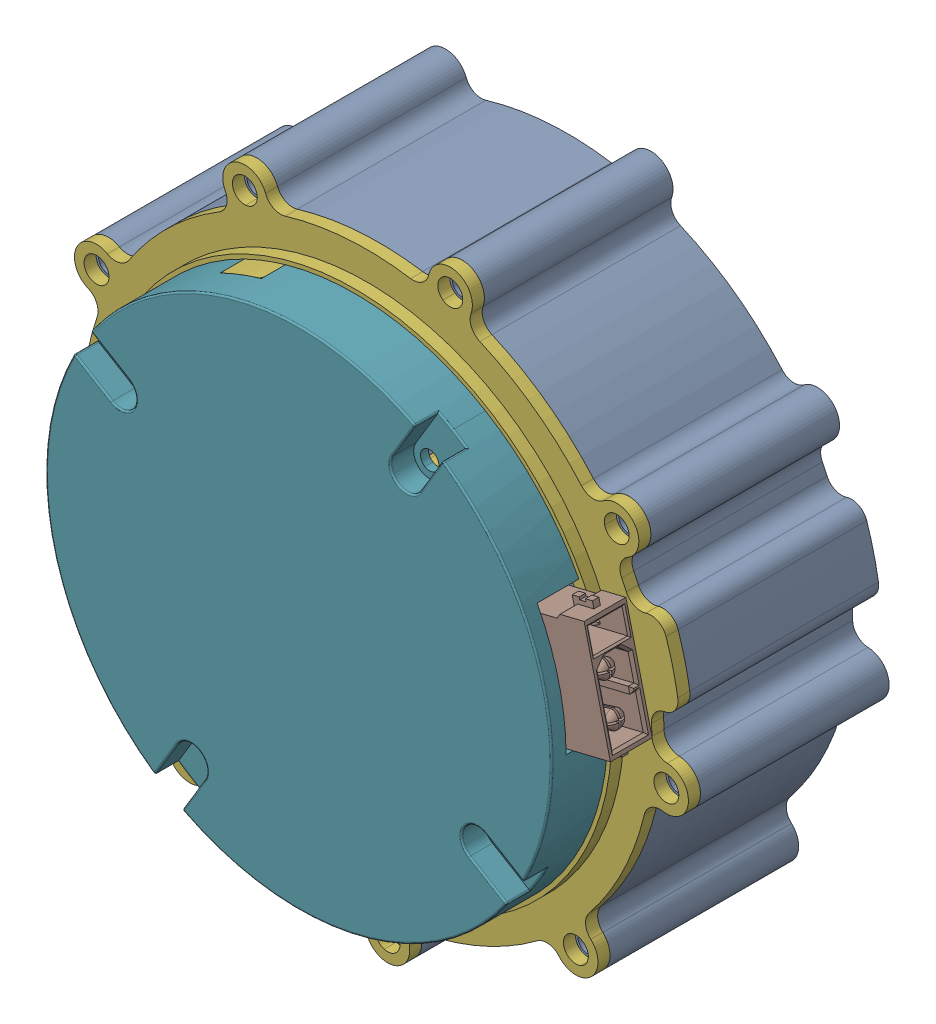
SolidWorks assembly 0714_ASM_1_ASM_1_ASM_1_ASM.stp, configuration 默认. Lengths in mm.
Overall size (96.28 96.17 36.5).
12 component instances, 8 part files, 0 mates.
Components (placement in the parent):
- 3_1_02_067_0003_ASM_ASM_1_ASM_1_ASM.stp-1: 3_1_02_067_0003_ASM_ASM_1_ASM_1_ASM.stp [默认] at origin size (96.28 96.17 36.5)
  - 3_1_02_067_0003_ASM_1_ASM_1_ASM_ASM.stp-1: 3_1_02_067_0003_ASM_1_ASM_1_ASM_ASM.stp [默认] at origin size (96.28 96.17 36.5)
    - 1_1_06_EB673-504_1_1_1_1_1.stp-1: 1_1_06_EB673-504_1_1_1_1_1.stp [默认] at (39.8324 39.833 -22) size (79.19 78.95 25.5)
    - 1_2_04_670601_1_1_1_1_1.stp-1: 1_2_04_670601_1_1_1_1_1.stp [默认] at (93.9161 79.9966 -44) size (37 37 4)
    - 1_1_02_EB671-500_1_1_1_1_1.stp-1: 1_1_02_EB671-500_1_1_1_1_1.stp [默认] at (93.9161 79.9966 -44.4) x (-0.960973 0.276644 0) z (0 0 1) size (33 33 8.5)
    - 1_2_04_694000_1_1_1_1_1.stp-1: 1_2_04_694000_1_1_1_1_1.stp [默认] at (93.9161 79.9966 -44.5) size (11 11 4)
    - 1_2_06_000213_1_1_1_1_1.stp-1: 1_2_06_000213_1_1_1_1_1.stp [默认] at (93.9161 79.9966 -45.5) size (38.8 36.2 1.5)
    - 1_1_31_QT-642_1_1_1_1_1.stp-1: 1_1_31_QT-642_1_1_1_1_1.stp [默认] at (93.9161 79.9966 -22) x (-0.970555 -0.24088 0) z (0 0 -1) size (79.5 79.36 6)
    - 1_1_06_EB673-502_1_1_1_1_1.stp-1: 1_1_06_EB673-502_1_1_1_1_1.stp [默认] at (93.9161 79.9966 -13) x (-0.515958 -0.856614 0) z (0 0 -1) size (63 63 8)
  - 0518_ASM_2_ASM_1_ASM_1_ASM_1_AS_ASM.stp-1: 0518_ASM_2_ASM_1_ASM_1_ASM_1_AS_ASM.stp [默认] at (93.9161 79.9966 -17.235) x (0.235897 -0.971778 0) z (0 0 1) size (15.5 11.3 5.2)
    - 12345_ASM_1_ASM_2_ASM_1_ASM_1_A_ASM.stp-1: 12345_ASM_1_ASM_2_ASM_1_ASM_1_A_ASM.stp [默认] at origin size (15.5 11.3 5.2)
      - DUANZI_1_3_1_1_1_1_1_1.stp-1: DUANZI_1_3_1_1_1_1_1_1.stp [默认] at (-0.1798 16.5474 0.4329) x (0 0 -1) z (0 1 0) size (5.2 15.5 11.3)
